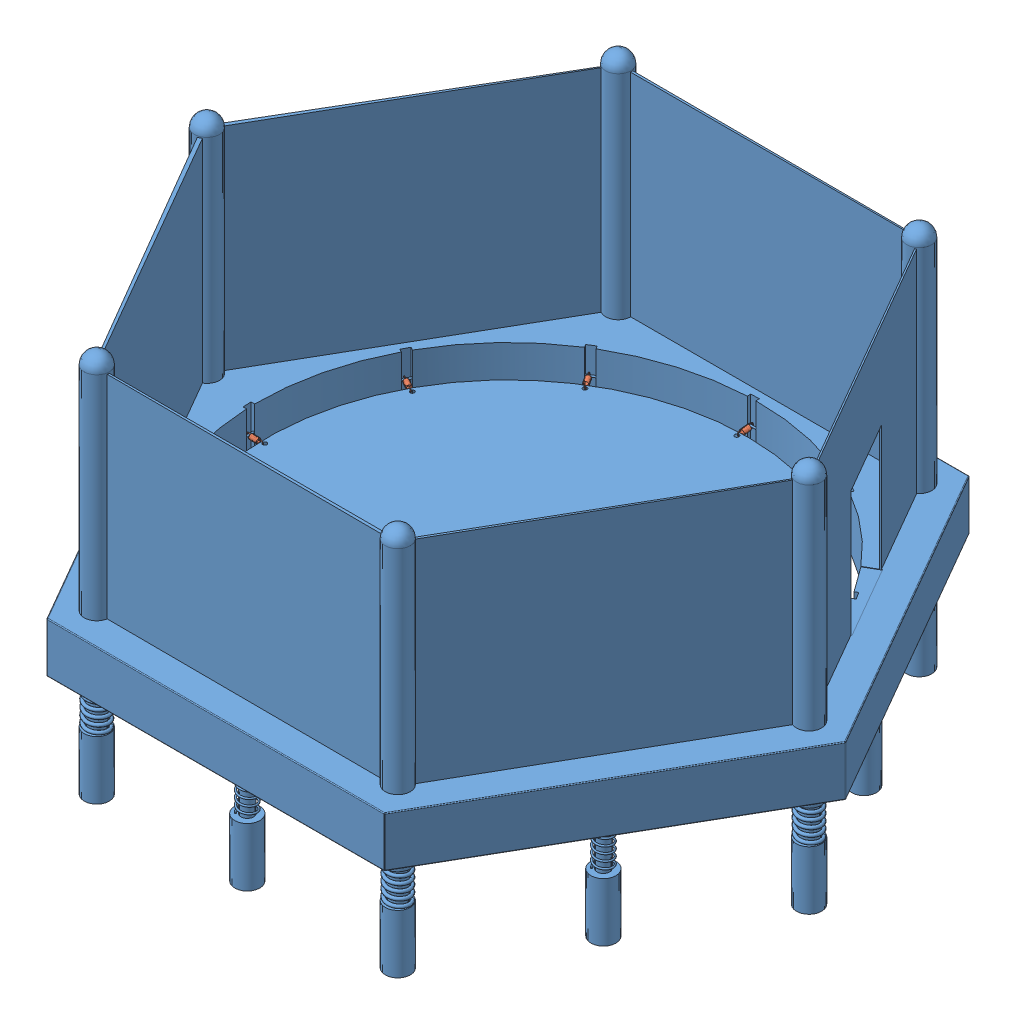
SolidWorks assembly AssemblyTrampoline, configuration Default. Lengths in mm.
Overall size (8079.81 4600 7000).
13 component instances, 2 part files, 0 mates.
Components (placement in the parent):
- Assingment3_Trampoline_Star_Chen-1: Assingment3_Trampoline_Star_Chen [Default] at (-1356.0368 8237.3238 -205.4221) size (8079.81 4600 7000)
- lecture4_springwithhook_21010264-1: lecture4_springwithhook_21010264 [Default] at (1093.5305 8234.1124 -1725.8195) x (0.846517 0.079321 -0.52642) z (0.505691 0.189256 0.8417) size (198.38 64.43 64.31)
- lecture4_springwithhook_21010264-2: lecture4_springwithhook_21010264 [Default] at (5.1521 8234.1124 -2746.9085) x (0.469895 0.079321 -0.879151) z (0.858791 0.189256 0.476088) size (198.38 64.43 64.31)
- lecture4_springwithhook_21010264-3: lecture4_springwithhook_21010264 [Default] at (-1447.9559 8234.1124 -3087.0084) x (-0.032635 0.079321 -0.996315) z (0.981779 0.189256 -0.017091) size (198.38 64.43 64.31)
- lecture4_springwithhook_21010264-4: lecture4_springwithhook_21010264 [Default] at (-2876.4342 8234.1124 -2654.9895) x (-0.52642 0.079321 -0.846517) z (0.8417 0.189256 -0.505691) size (198.38 64.43 64.31)
- lecture4_springwithhook_21010264-5: lecture4_springwithhook_21010264 [Default] at (-3897.5233 8234.1124 -1566.611) x (-0.879151 0.079321 -0.469895) z (0.476088 0.189256 -0.858791) size (198.38 64.43 64.31)
- lecture4_springwithhook_21010264-6: lecture4_springwithhook_21010264 [Default] at (-4237.6231 8234.1124 -113.5031) x (-0.996315 0.079321 0.032635) z (-0.017091 0.189256 -0.981779) size (198.38 64.43 64.31)
- lecture4_springwithhook_21010264-7: lecture4_springwithhook_21010264 [Default] at (-3805.6042 8234.1124 1314.9752) x (-0.846517 0.079321 0.52642) z (-0.505691 0.189256 -0.8417) size (198.38 64.43 64.31)
- lecture4_springwithhook_21010264-8: lecture4_springwithhook_21010264 [Default] at (-2717.2257 8234.1124 2336.0643) x (-0.469895 0.079321 0.879151) z (-0.858791 0.189256 -0.476088) size (198.38 64.43 64.31)
- lecture4_springwithhook_21010264-9: lecture4_springwithhook_21010264 [Default] at (-1264.1178 8234.1124 2676.1641) x (0.032635 0.079321 0.996315) z (-0.981779 0.189256 0.017091) size (198.38 64.43 64.31)
- lecture4_springwithhook_21010264-10: lecture4_springwithhook_21010264 [Default] at (164.3605 8234.1124 2244.1453) x (0.52642 0.079321 0.846517) z (-0.8417 0.189256 0.505691) size (198.38 64.43 64.31)
- lecture4_springwithhook_21010264-11: lecture4_springwithhook_21010264 [Default] at (1185.4496 8234.1124 1155.7668) x (0.879151 0.079321 0.469895) z (-0.476088 0.189256 0.858791) size (198.38 64.43 64.31)
- lecture4_springwithhook_21010264-12: lecture4_springwithhook_21010264 [Default] at (1525.5494 8234.1124 -297.3412) x (0.996315 0.079321 -0.032635) z (0.017091 0.189256 0.981779) size (198.38 64.43 64.31)
